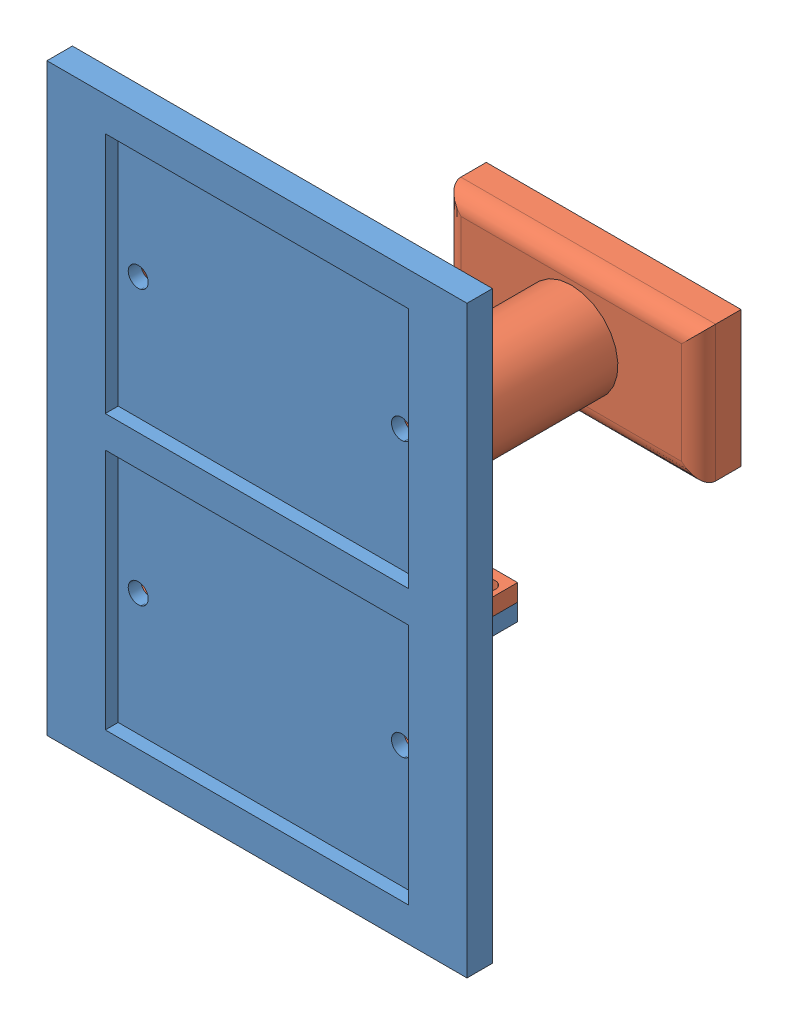
SolidWorks assembly Solar Panel Assembly, configuration Default. Lengths in mm.
Overall size (62.81 87.38 53.34).
2 component instances, 2 part files, 2 mates.
Components (placement in the parent):
- Front View Sketch-1: Front View Sketch [Default] at origin size (62.81 87.38 8.89)
- SolarPanel Wire Enlcosure-1: SolarPanel Wire Enlcosure [Default] at (0 -0.127 -3.81) x (-1 0 0) z (0 -1 0) size (60.17 49.53 51.49)
Mates (geometry in assembly coordinates):
- Concentric1: concentric anti-aligned: circle of Front View Sketch-1; circle of SolarPanel Wire Enlcosure-1
- Coincident2: coincident anti-aligned: plane of Front View Sketch-1 through (30.0854 -0.127 -8.89) normal (0 1 0); plane of SolarPanel Wire Enlcosure-1 through (0 -0.127 -8.89) normal (0 -1 0)
